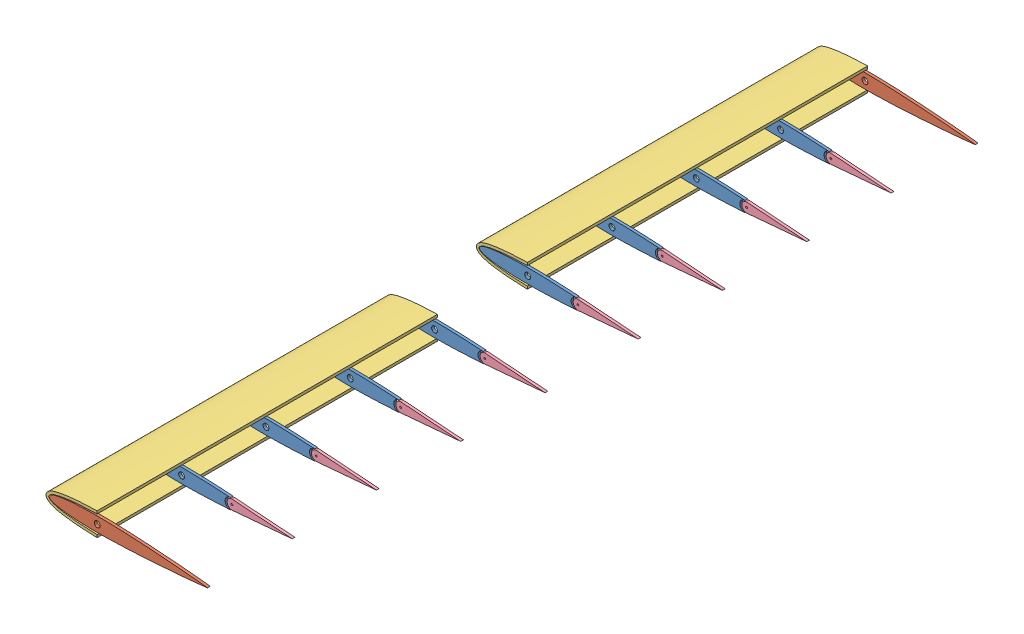
SolidWorks assembly horizontal_stabilizer, configuration Default. Lengths in mm.
Overall size (136.56 19.64 649.96).
20 component instances, 4 part files, 0 mates.
Components (placement in the parent):
- HSrib_cut-1: HSrib_cut [Default] at origin size (84.22 12.08 2.29)
- HSrib_cut-2: HSrib_cut [Default] at (0 0 71.12) size (84.22 12.08 2.29)
- HSrib_cut-3: HSrib_cut [Default] at (0 0 142.24) size (84.22 12.08 2.29)
- HSrib_cut-4: HSrib_cut [Default] at (0 0 213.36) size (84.22 12.08 2.29)
- Hortwin-1: Hortwin [Default] at (0.0033 0.0346 284.5392) size (134.23 12.08 2.29)
- elevator_cover-1: elevator_cover [Default] at (-0.0789 -0.0124 -0.1404) size (43.2 19.64 287.02)
- elevator-1: elevator [Default] at (83.2445 -0.0127 0.0021) size (54.86 8.13 2.29)
- elevator-2: elevator [Default] at (83.2445 -0.0127 71.1221) size (54.86 8.13 2.29)
- elevator-3: elevator [Default] at (83.2445 -0.0127 142.2421) size (54.86 8.13 2.29)
- elevator-4: elevator [Default] at (83.2445 -0.0127 213.3621) size (54.86 8.13 2.29)
- HSrib_cut-5: HSrib_cut [Default] at (0 0 -78.486) size (84.22 12.08 2.29)
- Hortwin-2: Hortwin [Default] at (0.0033 0.0346 -363.0252) size (134.23 12.08 2.29)
- elevator_cover-2: elevator_cover [Default] at (-0.0789 -0.0124 -363.0796) size (43.2 19.64 287.02)
- elevator-5: elevator [Default] at (83.2445 -0.0127 -78.4881) size (54.86 8.13 2.29)
- HSrib_cut-6: HSrib_cut [Default] at (0 0 -149.606) size (84.22 12.08 2.29)
- HSrib_cut-7: HSrib_cut [Default] at (0 0 -220.726) size (84.22 12.08 2.29)
- HSrib_cut-8: HSrib_cut [Default] at (0 0 -291.846) size (84.22 12.08 2.29)
- elevator-6: elevator [Default] at (83.2445 -0.0127 -149.6081) size (54.86 8.13 2.29)
- elevator-7: elevator [Default] at (83.2445 -0.0127 -220.7281) size (54.86 8.13 2.29)
- elevator-8: elevator [Default] at (83.2445 -0.0127 -291.8481) size (54.86 8.13 2.29)
